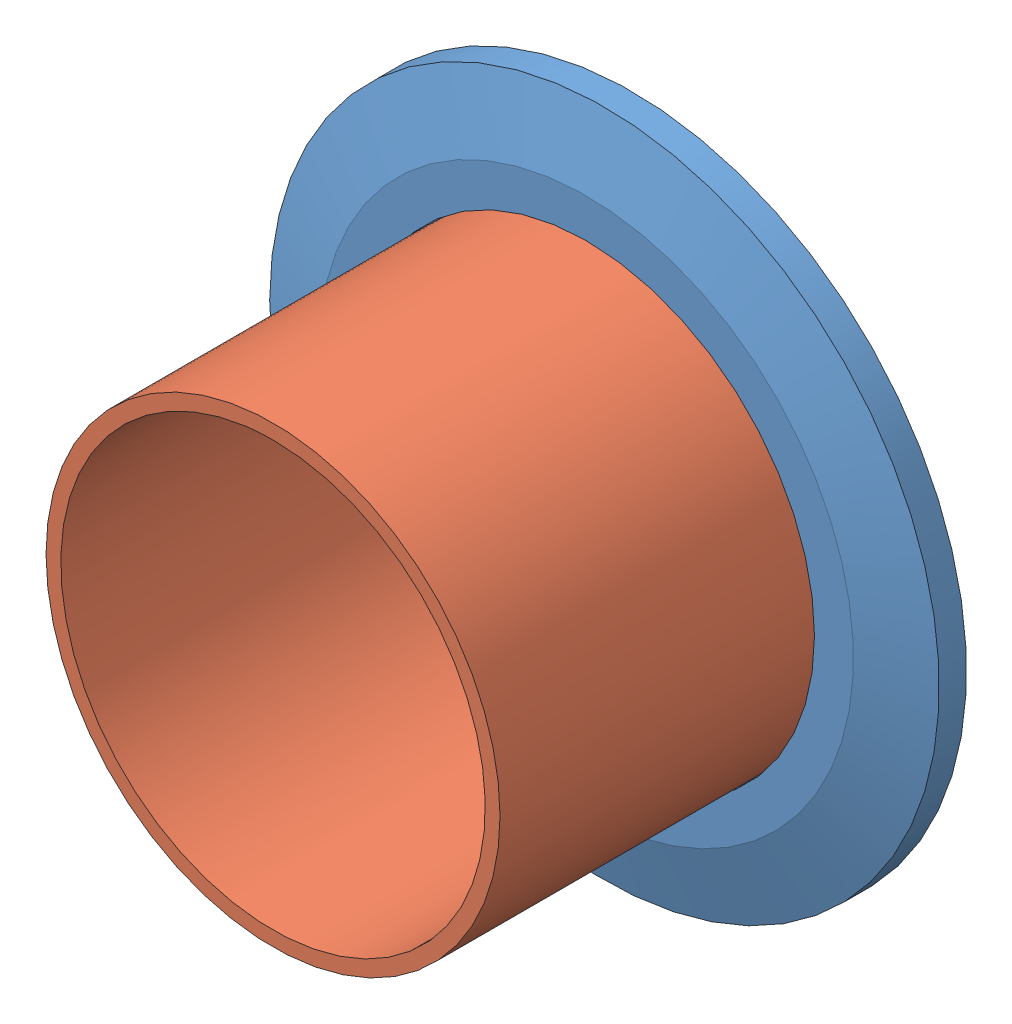
SolidWorks assembly 715109, configuration Default. Lengths in mm.
Overall size (74.93 74.93 40.14).
2 component instances, 2 part files, 2 mates.
Components (placement in the parent):
- 713022-1: 713022 [Default] at (54.2462 -60.375 78.418) size (74.93 74.93 5.08)
- 971504-REV.B-1: 971504-REV.B [Default] at (54.2462 -60.375 82.487) x (-0.063338 0.997992 0) z (0 0 1) size (50.8 50.8 36.07)
Mates (geometry in assembly coordinates):
- Concentric1: concentric: cylinder of 713022-1 through (54.2462 -60.375 78.418) axis (0 0 -1) radius 23.749; cylinder of 971504-REV.B-1 through (54.2462 -60.375 118.555) axis (0 0 -1) radius 25.4
- Parallel1: parallel anti-aligned: plane of 713022-1 through (77.9952 -60.375 82.482) normal (0 0 1); plane of 971504-REV.B-1 through (54.2462 -60.375 82.487) normal (0 0 -1)
